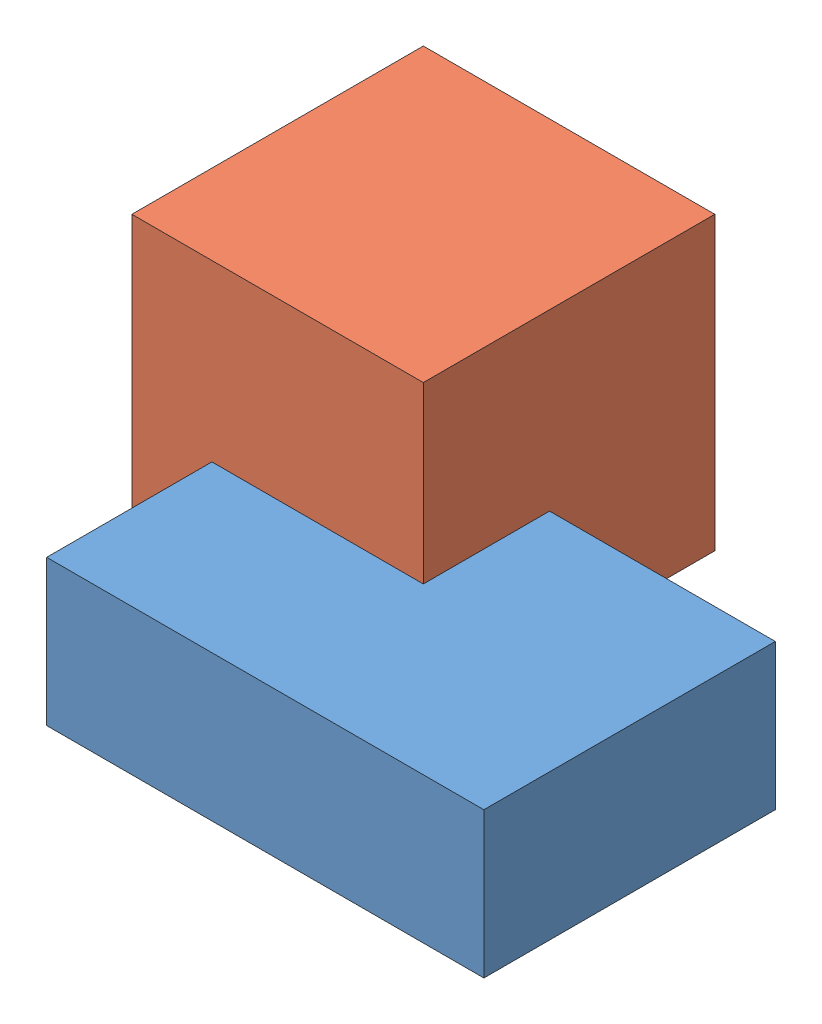
SolidWorks assembly Assem1, configuration Default. Lengths in mm.
Overall size (177.46 109.85 156.69).
2 component instances, 2 part files, 0 mates.
Components (placement in the parent):
- GreenBlock-1: GreenBlock [Default] at (32.1465 76.2052 112.144) size (150 50 100)
- PinkBlock-1: PinkBlock [Default] at (-20.3142 86.0555 55.4518) size (100 100 100)
